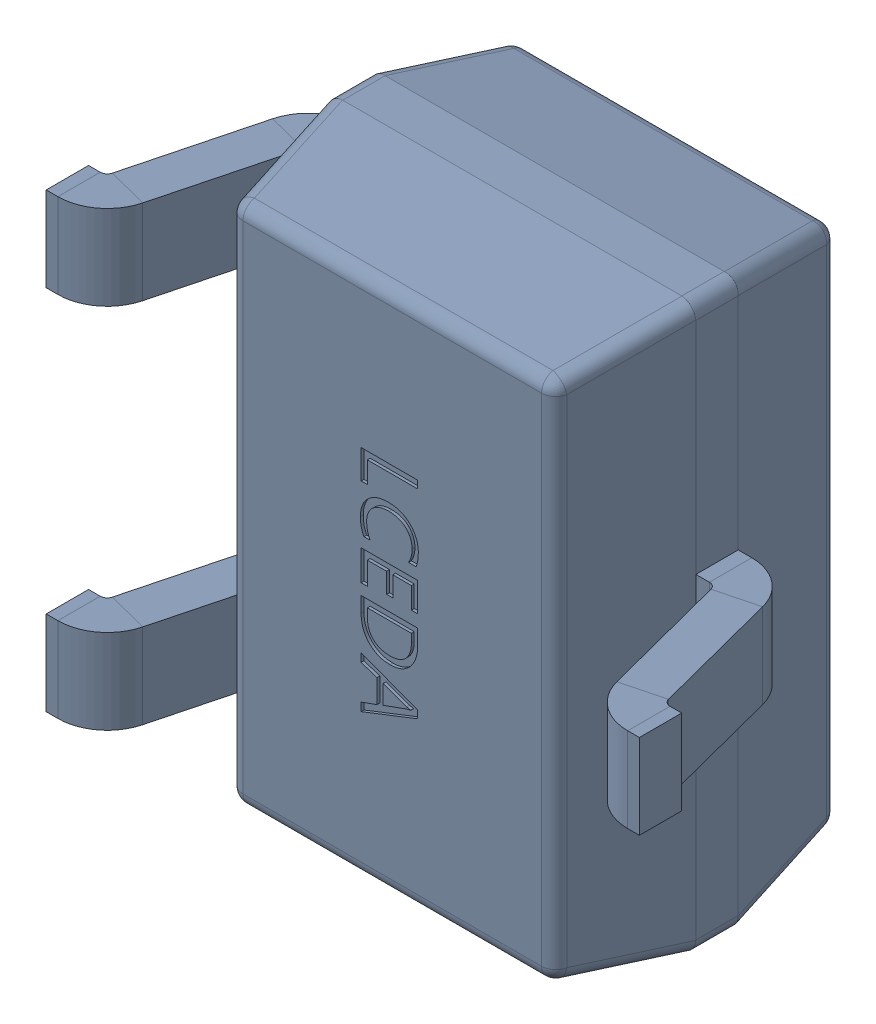
SolidWorks assembly Q15, configuration Défaut. Lengths in mm.
Overall size (2.1 2 1.18).
4 component instances, 1 part files, 0 mates.
Components (placement in the parent):
- SOT-323-1: SOT-323 [Défaut] at (14.5263 4.4817 -0.4818) x (-1 0 0) z (0 0 -1) size (2.1 2 1.18)
  - D1.step-1: D1.step [Défaut] at (5.0775 -6.7805 1.6001) size (2.1 2 1.18)
    - SOT-323_L2.0-W1.3-P1.30-LS2.1-BR.step-1: SOT-323_L2.0-W1.3-P1.30-LS2.1-BR.step [Défaut] at origin size (2.1 2 1.18)
      - COMPOUND.step_247-1: COMPOUND.step_247 [Défaut] at origin size (2.1 2 1.18)
